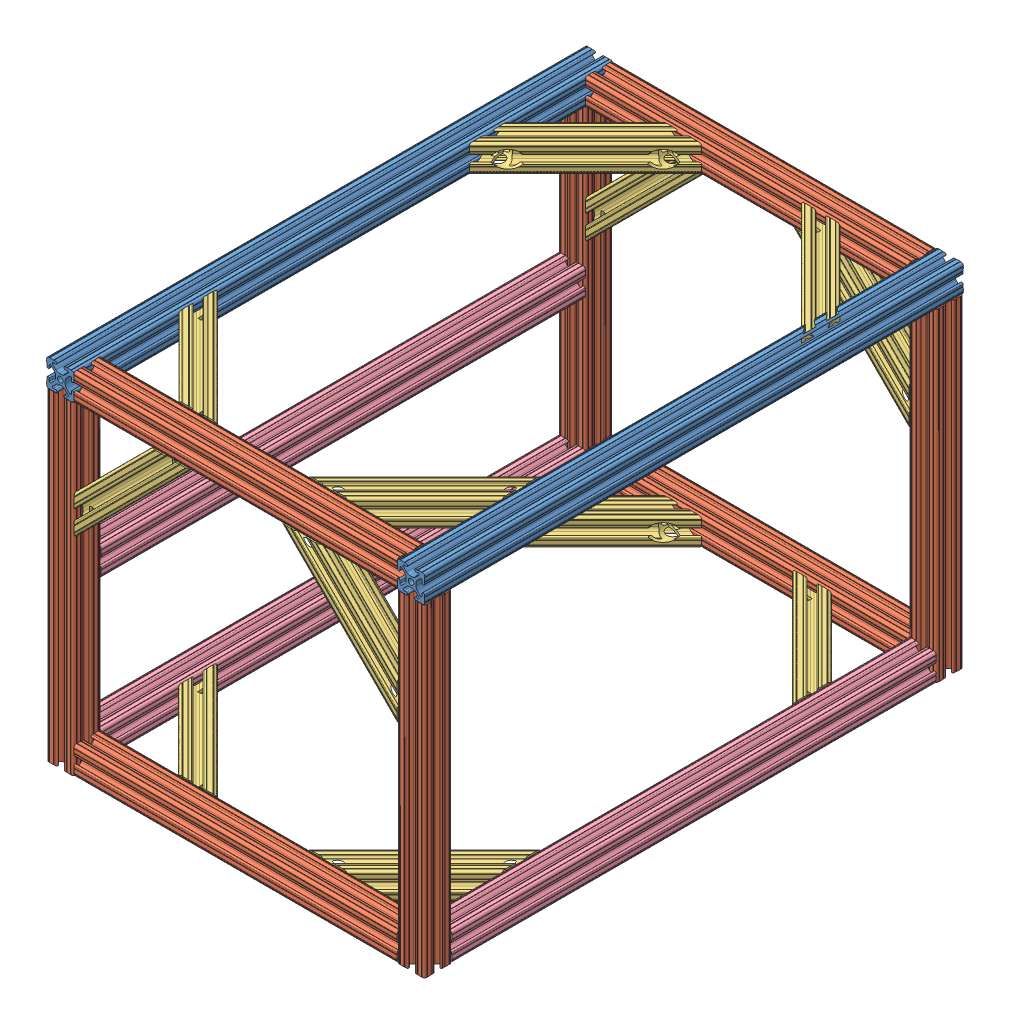
SolidWorks assembly frame, configuration Default. Lengths in mm.
Overall size (919.2 919.2 635.29).
25 component instances, 4 part files, 71 mates.
Components (placement in the parent):
- 50cm_8020-1: 50cm_8020 [47065T121] at (308.8862 430.7033 348.5131) size (25.48 25.48 609.6)
- 30cm_8020-1: 30cm_8020 [47065T121] at (11.9947 430.7033 945.4046) x (0 0 -1) z (1 0 0) size (25.48 25.48 609.6)
- Corner-1: Corner [47065T186] at (366.496 430.7033 887.7948) x (0 -1 0) z (0.707107 0 0.707107) size (25.4 25.5 152.4)
- 50cm_8020-2: 50cm_8020 [47065T121] at (634.3032 430.7033 348.3131) size (25.48 25.48 609.6)
- Corner-2: Corner [47065T186] at (576.6934 430.7033 887.7948) x (0 1 0) z (-0.707107 0 0.707107) size (25.4 25.5 152.4)
- 30cm_8020-2: 30cm_8020 [47065T121] at (11.9947 430.7033 470.6216) x (0 0 -1) z (1 0 0) size (25.48 25.48 609.6)
- Corner-3: Corner [47065T186] at (584.8934 430.7033 528.2314) x (0 1 0) z (0.707107 0 0.707107) size (25.4 25.5 152.4)
- Corner-4: Corner [47065T186] at (366.496 430.7033 528.2314) x (0 -1 0) z (-0.707107 0 0.707107) size (25.4 25.5 152.4)
- 30cm_8020-3: 30cm_8020 [47065T121] at (634.3032 727.5948 470.4216) x (1 0 0) z (0 -1 0) size (25.48 25.48 609.6)
- 30cm_8020-4: 30cm_8020 [47065T121] at (308.8862 727.5948 470.6216) x (1 0 0) z (0 -1 0) size (25.48 25.48 609.6)
- 30cm_8020-5: 30cm_8020 [47065T121] at (308.8862 727.5948 945.6046) x (1 0 0) z (0 -1 0) size (25.48 25.48 609.6)
- 30cm_8020-6: 30cm_8020 [47065T121] at (634.3032 -191.6052 945.4046) x (1 0 0) z (0 1 0) size (25.48 25.48 609.6)
- Corner-5: Corner [47065T186] at (366.496 373.0935 945.4046) x (0 0 1) z (0.707107 0.707107 0) size (25.4 25.5 152.4)
- Corner-6: Corner [47065T186] at (576.6934 373.0935 945.4046) x (0 0 -1) z (-0.707107 0.707107 0) size (25.4 25.5 152.4)
- Corner-7: Corner [47065T186] at (576.6934 373.0935 470.4216) x (0 0 -1) z (-0.707107 0.707107 0) size (25.4 25.5 152.4)
- Corner-8: Corner [47065T186] at (366.496 373.0935 470.6216) x (0 0 1) z (0.707107 0.707107 0) size (25.4 25.5 152.4)
- 30cm_8020-7: 30cm_8020 [47065T121] at (931.1947 130.7033 945.6046) x (0 0 1) z (-1 0 0) size (25.48 25.48 609.6)
- 30cm_8020-8: 30cm_8020 [47065T121] at (931.1947 130.5033 470.4216) x (0 0 1) z (-1 0 0) size (25.48 25.48 609.6)
- 44.96cm_8020-1: 44.96cm_8020 [47065T121] at (634.3032 130.5033 323.0961) size (25.48 25.48 609.6)
- 44.96cm_8020-2: 44.96cm_8020 [47065T121] at (308.8862 130.5033 323.2961) size (25.48 25.48 609.6)
- Corner-9: Corner [47065T186] at (366.496 130.5033 887.9948) x (0 1 0) z (-0.707107 0 -0.707107) size (25.4 25.5 152.4)
- Corner-10: Corner [47065T186] at (366.496 130.5033 528.0314) x (0 1 0) z (0.707107 0 -0.707107) size (25.4 25.5 152.4)
- Corner-11: Corner [47065T186] at (576.6934 130.7033 887.9948) x (0 -1 0) z (0.707107 0 -0.707107) size (25.4 25.5 152.4)
- Corner-12: Corner [47065T186] at (576.6934 130.5033 528.0314) x (0 -1 0) z (-0.707107 0 -0.707107) size (25.4 25.5 152.4)
- 44.96cm_8020-3: 44.96cm_8020 [47065T121] at (308.8862 277.4084 323.2961) size (25.48 25.48 609.6)
Mates (geometry in assembly coordinates):
- Coincident7: coincident aligned: plane of 50cm_8020-1 through (307.7709 426.1948 958.1131) normal (0 -1 0); plane of 30cm_8020-1 through (621.5947 426.1948 946.5199) normal (0 -1 0)
- Distance5: distance = 8.2 mm anti-aligned: plane of 50cm_8020-1 through (313.3947 429.588 958.1131) normal (1 0 0); plane of Corner-1 through (321.5947 468.8033 824.933) normal (-1 0 0)
- Distance6: distance = 8.2 mm anti-aligned: plane of Corner-1 through (393.4368 468.8033 932.6961) normal (0 0 1); plane of 30cm_8020-1 through (621.5947 429.588 940.8961) normal (0 0 -1)
- Coincident14: coincident aligned: plane of 50cm_8020-1 through (307.7709 426.1948 958.1131) normal (0 -1 0); plane of Corner-1 through (482.4507 426.1948 1005.3268) normal (0 -1 0)
- Distance7: distance = 8.2 mm anti-aligned: plane of 30cm_8020-1 through (621.5947 441.1935 955.8948) normal (1 0 0); plane of 50cm_8020-2 through (629.7947 429.588 957.9131) normal (-1 0 0)
- Distance8: distance = 8 mm aligned: plane of 50cm_8020-2 through (623.813 441.1935 957.9131) normal (0 0 1); plane of 30cm_8020-1 through (621.5947 429.588 949.9131) normal (0 0 1)
- Coincident17: coincident aligned: plane of 30cm_8020-1 through (621.5947 435.2118 946.5199) normal (0 1 0); plane of 50cm_8020-2 through (633.1879 435.2118 957.9131) normal (0 1 0)
- Distance9: distance = 8.2 mm anti-aligned: plane of Corner-2 through (549.7527 392.6033 932.6961) normal (0 0 1); plane of 30cm_8020-1 through (621.5947 429.588 940.8961) normal (0 0 -1)
- Distance10: distance = 8.2 mm anti-aligned: plane of Corner-2 through (621.5947 392.6033 824.933) normal (1 0 0); plane of 50cm_8020-2 through (629.7947 429.588 957.9131) normal (-1 0 0)
- Coincident20: coincident aligned: plane of 30cm_8020-1 through (621.5947 426.1948 946.5199) normal (0 -1 0); plane of Corner-2 through (460.7387 426.1948 1005.3268) normal (0 -1 0)
- Distance11: distance = 8.2 mm anti-aligned: plane of 30cm_8020-1 through (321.5947 456.9581 1022.6955) normal (-1 0 0); plane of 50cm_8020-1 through (313.3947 429.588 958.1131) normal (1 0 0)
- Distance12: distance = 8.2 mm aligned: plane of 50cm_8020-1 through (298.396 441.1935 958.1131) normal (0 0 1); plane of 30cm_8020-1 through (621.5947 429.588 949.9131) normal (0 0 1)
- Distance18: distance = 8.2 mm anti-aligned: plane of 30cm_8020-2 through (321.5947 456.9581 547.9125) normal (-1 0 0); plane of 50cm_8020-1 through (313.3947 429.588 958.1131) normal (1 0 0)
- Distance19: distance = 8 mm aligned: plane of 30cm_8020-2 through (621.5947 429.588 466.1131) normal (0 0 -1); plane of 50cm_8020-1 through (270.6386 454.38 458.1131) normal (0 0 -1)
- Coincident31: coincident aligned: plane of 50cm_8020-1 through (307.7709 435.2118 958.1131) normal (0 1 0); plane of 30cm_8020-2 through (621.5947 435.2118 471.7369) normal (0 1 0)
- Distance22: distance = 0 mm aligned: plane of 30cm_8020-2 through (621.5947 435.2118 471.7369) normal (0 1 0); plane of Corner-3 through (702.4254 435.2118 644.1861) normal (0 1 0)
- Distance21: distance = 8.2 mm anti-aligned: plane of Corner-3 through (522.0316 392.6033 483.3301) normal (0 0 -1); plane of 30cm_8020-2 through (621.5947 429.588 475.1301) normal (0 0 1)
- Coincident35: coincident anti-aligned: plane of 50cm_8020-2 through (629.7947 429.588 957.9131) normal (-1 0 0); plane of Corner-3 through (629.7947 392.6033 555.1722) normal (1 0 0)
- Distance25: distance = 8.2 mm anti-aligned: plane of 50cm_8020-1 through (313.3947 429.588 958.1131) normal (1 0 0); plane of Corner-4 through (321.5947 468.8033 555.1722) normal (-1 0 0)
- Distance23: distance = 8.2 mm anti-aligned: plane of Corner-4 through (429.3578 468.8033 483.3301) normal (0 0 -1); plane of 30cm_8020-2 through (621.5947 429.588 475.1301) normal (0 0 1)
- Coincident38: coincident aligned: plane of 50cm_8020-1 through (307.7709 435.2118 958.1131) normal (0 1 0); plane of Corner-4 through (248.964 435.2118 644.1861) normal (0 1 0)
- Distance26: distance = 8.2 mm anti-aligned: plane of 30cm_8020-3 through (557.0123 417.9948 496.6764) normal (0 1 0); plane of 50cm_8020-2 through (633.1879 426.1948 957.9131) normal (0 -1 0)
- Distance27: distance = 8 mm aligned: plane of 30cm_8020-3 through (633.1879 117.9948 465.9131) normal (0 0 -1); plane of 50cm_8020-2 through (596.0556 454.38 457.9131) normal (0 0 -1)
- Coincident41: coincident aligned: plane of 50cm_8020-2 through (638.8117 429.588 957.9131) normal (1 0 0); plane of 30cm_8020-3 through (638.8117 117.9948 469.3063) normal (1 0 0)
- Distance28: distance = 8.2 mm anti-aligned: plane of 30cm_8020-4 through (231.5953 417.9948 496.8764) normal (0 1 0); plane of 50cm_8020-1 through (307.7709 426.1948 958.1131) normal (0 -1 0)
- Distance29: distance = 8 mm aligned: plane of 30cm_8020-4 through (307.7709 117.9948 466.1131) normal (0 0 -1); plane of 50cm_8020-1 through (270.6386 454.38 458.1131) normal (0 0 -1)
- Coincident44: coincident aligned: plane of 50cm_8020-1 through (304.3777 429.588 958.1131) normal (-1 0 0); plane of 30cm_8020-4 through (304.3777 117.9948 469.5063) normal (-1 0 0)
- Distance30: distance = 8 mm aligned: plane of 30cm_8020-5 through (307.7709 117.9948 950.1131) normal (0 0 1); plane of 50cm_8020-1 through (298.396 441.1935 958.1131) normal (0 0 1)
- Distance31: distance = 8.2 mm anti-aligned: plane of 30cm_8020-5 through (231.5953 417.9948 971.8594) normal (0 1 0); plane of 50cm_8020-1 through (307.7709 426.1948 958.1131) normal (0 -1 0)
- Coincident47: coincident aligned: plane of 50cm_8020-1 through (304.3777 429.588 958.1131) normal (-1 0 0); plane of 30cm_8020-5 through (304.3777 117.9948 944.4893) normal (-1 0 0)
- Distance32: distance = 8.2 mm anti-aligned: plane of 30cm_8020-6 through (623.813 417.9948 934.9144) normal (0 1 0); plane of 50cm_8020-2 through (633.1879 426.1948 957.9131) normal (0 -1 0)
- Distance33: distance = 8 mm aligned: plane of 30cm_8020-6 through (633.1879 417.9948 949.9131) normal (0 0 1); plane of 50cm_8020-2 through (623.813 441.1935 957.9131) normal (0 0 1)
- Coincident50: coincident aligned: plane of 50cm_8020-2 through (638.8117 429.588 957.9131) normal (1 0 0); plane of 30cm_8020-6 through (638.8117 417.9948 946.5199) normal (1 0 0)
- Distance35: distance = 8.2 mm anti-aligned: plane of Corner-5 through (321.5947 310.2317 907.3046) normal (-1 0 0); plane of 30cm_8020-5 through (313.3947 117.9948 944.4893) normal (1 0 0)
- Distance36: distance = 8.2 mm anti-aligned: plane of Corner-5 through (393.4368 417.9948 907.3046) normal (0 1 0); plane of 30cm_8020-1 through (621.5947 426.1948 946.5199) normal (0 -1 0)
- Coincident56: coincident aligned: plane of 30cm_8020-1 through (621.5947 429.588 949.9131) normal (0 0 1); plane of Corner-5 through (482.4507 490.6254 949.9131) normal (0 0 1)
- Distance37: distance = 8.2 mm anti-aligned: plane of Corner-6 through (549.7527 417.9948 983.5046) normal (0 1 0); plane of 30cm_8020-1 through (621.5947 426.1948 946.5199) normal (0 -1 0)
- Distance38: distance = 8.2 mm anti-aligned: plane of 30cm_8020-6 through (629.7947 417.9948 946.5199) normal (-1 0 0); plane of Corner-6 through (621.5947 310.2317 983.5046) normal (1 0 0)
- Coincident59: coincident aligned: plane of 30cm_8020-6 through (633.1879 417.9948 949.9131) normal (0 0 1); plane of Corner-6 through (460.7387 490.6254 949.9131) normal (0 0 1)
- Distance39: distance = 8.2 mm anti-aligned: plane of Corner-7 through (621.5947 310.2317 508.5216) normal (1 0 0); plane of 30cm_8020-3 through (629.7947 117.9948 469.3063) normal (-1 0 0)
- Distance40: distance = 8.2 mm anti-aligned: plane of Corner-7 through (549.7527 417.9948 508.5216) normal (0 1 0); plane of 30cm_8020-2 through (621.5947 426.1948 471.7369) normal (0 -1 0)
- Coincident62: coincident aligned: plane of 30cm_8020-3 through (633.1879 117.9948 465.9131) normal (0 0 -1); plane of Corner-7 through (460.7387 490.6254 465.9131) normal (0 0 -1)
- Distance41: distance = 8.2 mm anti-aligned: plane of Corner-8 through (321.5947 310.2317 432.5216) normal (-1 0 0); plane of 30cm_8020-4 through (313.3947 117.9948 469.5063) normal (1 0 0)
- Distance42: distance = 8.2 mm anti-aligned: plane of Corner-8 through (393.4368 417.9948 432.5216) normal (0 1 0); plane of 30cm_8020-2 through (621.5947 426.1948 471.7369) normal (0 -1 0)
- Coincident65: coincident aligned: plane of 30cm_8020-4 through (307.7709 117.9948 466.1131) normal (0 0 -1); plane of Corner-8 through (482.4507 490.6254 466.1131) normal (0 0 -1)
- Distance43: distance = 8.2 mm anti-aligned: plane of 30cm_8020-7 through (321.5947 141.1935 935.1144) normal (-1 0 0); plane of 30cm_8020-5 through (313.3947 117.9948 944.4893) normal (1 0 0)
- Distance44: distance = 8.2 mm aligned: plane of 30cm_8020-7 through (321.5947 126.1948 944.4893) normal (0 -1 0); plane of 30cm_8020-5 through (298.396 117.9948 956.0948) normal (0 -1 0)
- Coincident68: coincident aligned: plane of 30cm_8020-5 through (307.7709 117.9948 950.1131) normal (0 0 1); plane of 30cm_8020-7 through (321.5947 129.588 950.1131) normal (0 0 1)
- Distance45: distance = 8.2 mm anti-aligned: plane of 30cm_8020-3 through (629.7947 117.9948 469.3063) normal (-1 0 0); plane of 30cm_8020-8 through (621.5947 156.7581 393.1307) normal (1 0 0)
- Coincident70: coincident aligned: plane of 30cm_8020-3 through (633.1879 117.9948 465.9131) normal (0 0 -1); plane of 30cm_8020-8 through (321.5947 129.388 465.9131) normal (0 0 -1)
- Distance46: distance = 8 mm aligned: plane of 30cm_8020-8 through (321.5947 125.9948 469.3063) normal (0 -1 0); plane of 30cm_8020-3 through (623.813 117.9948 480.9118) normal (0 -1 0)
- Distance47: distance = 8.2 mm anti-aligned: plane of 44.96cm_8020-1 through (623.813 140.9935 932.6961) normal (0 0 1); plane of 30cm_8020-6 through (633.1879 417.9948 940.8961) normal (0 0 -1)
- Coincident73: coincident aligned: plane of 30cm_8020-6 through (638.8117 417.9948 946.5199) normal (1 0 0); plane of 44.96cm_8020-1 through (638.8117 129.388 932.6961) normal (1 0 0)
- Distance48: distance = 8 mm aligned: plane of 30cm_8020-6 through (557.0123 117.9948 919.1498) normal (0 -1 0); plane of 44.96cm_8020-1 through (633.1879 125.9948 932.6961) normal (0 -1 0)
- Coincident75: coincident aligned: plane of 30cm_8020-5 through (304.3777 117.9948 944.4893) normal (-1 0 0); plane of 44.96cm_8020-2 through (304.3777 129.388 932.8961) normal (-1 0 0)
- Distance49: distance = 8.2 mm anti-aligned: plane of 44.96cm_8020-2 through (298.396 140.9935 932.8961) normal (0 0 1); plane of 30cm_8020-5 through (307.7709 117.9948 941.0961) normal (0 0 -1)
- Distance50: distance = 8 mm aligned: plane of 30cm_8020-5 through (298.396 117.9948 956.0948) normal (0 -1 0); plane of 44.96cm_8020-2 through (307.7709 125.9948 932.8961) normal (0 -1 0)
- Coincident78: coincident aligned: plane of 44.96cm_8020-2 through (307.7709 125.9948 932.8961) normal (0 -1 0); plane of Corner-9 through (248.964 125.9948 772.0401) normal (0 -1 0)
- Distance51: distance = 8.2 mm anti-aligned: plane of Corner-9 through (321.5947 92.4033 861.0541) normal (-1 0 0); plane of 44.96cm_8020-2 through (313.3947 129.388 932.8961) normal (1 0 0)
- Distance52: distance = 8.2 mm anti-aligned: plane of Corner-9 through (429.3578 92.4033 932.8961) normal (0 0 1); plane of 30cm_8020-7 through (321.5947 129.588 941.0961) normal (0 0 -1)
- Coincident81: coincident aligned: plane of 44.96cm_8020-2 through (307.7709 125.9948 932.8961) normal (0 -1 0); plane of Corner-10 through (482.4507 125.9948 410.4994) normal (0 -1 0)
- Distance53: distance = 8.2 mm anti-aligned: plane of Corner-10 through (321.5947 92.4033 590.8932) normal (-1 0 0); plane of 44.96cm_8020-2 through (313.3947 129.388 932.8961) normal (1 0 0)
- Distance54: distance = 8.2 mm anti-aligned: plane of Corner-10 through (393.4368 92.4033 483.1301) normal (0 0 -1); plane of 30cm_8020-8 through (321.5947 129.388 474.9301) normal (0 0 1)
- Distance57: distance = 8.2 mm anti-aligned: plane of Corner-11 through (621.5947 168.8033 861.0541) normal (1 0 0); plane of 44.96cm_8020-1 through (629.7947 129.388 932.6961) normal (-1 0 0)
- Distance58: distance = 8.2 mm anti-aligned: plane of Corner-11 through (513.8316 168.8033 932.8961) normal (0 0 1); plane of 30cm_8020-7 through (321.5947 129.588 941.0961) normal (0 0 -1)
- Coincident91: coincident aligned: plane of 30cm_8020-7 through (321.5947 126.1948 944.4893) normal (0 -1 0); plane of Corner-11 through (694.2254 126.1948 772.0401) normal (0 -1 0)
- Distance59: distance = 8.2 mm anti-aligned: plane of Corner-12 through (621.5947 168.6033 590.8932) normal (1 0 0); plane of 44.96cm_8020-1 through (629.7947 129.388 932.6961) normal (-1 0 0)
- Distance60: distance = 8.2 mm anti-aligned: plane of Corner-12 through (549.7527 168.6033 483.1301) normal (0 0 -1); plane of 30cm_8020-8 through (321.5947 129.388 474.9301) normal (0 0 1)
- Coincident94: coincident aligned: plane of 44.96cm_8020-1 through (633.1879 125.9948 932.6961) normal (0 -1 0); plane of Corner-12 through (460.7387 125.9948 410.4994) normal (0 -1 0)
- Distance61: distance = 8.2 mm: plane of 44.96cm_8020-3 through (298.396 287.8986 932.8961) normal (0 0 1); plane of 30cm_8020-5 through (307.7709 117.9948 941.0961) normal (0 0 -1)
- Coincident96: coincident aligned: plane of 30cm_8020-5 through (304.3777 117.9948 944.4893) normal (-1 0 0); plane of 44.96cm_8020-3 through (304.3777 276.2932 932.8961) normal (-1 0 0)
